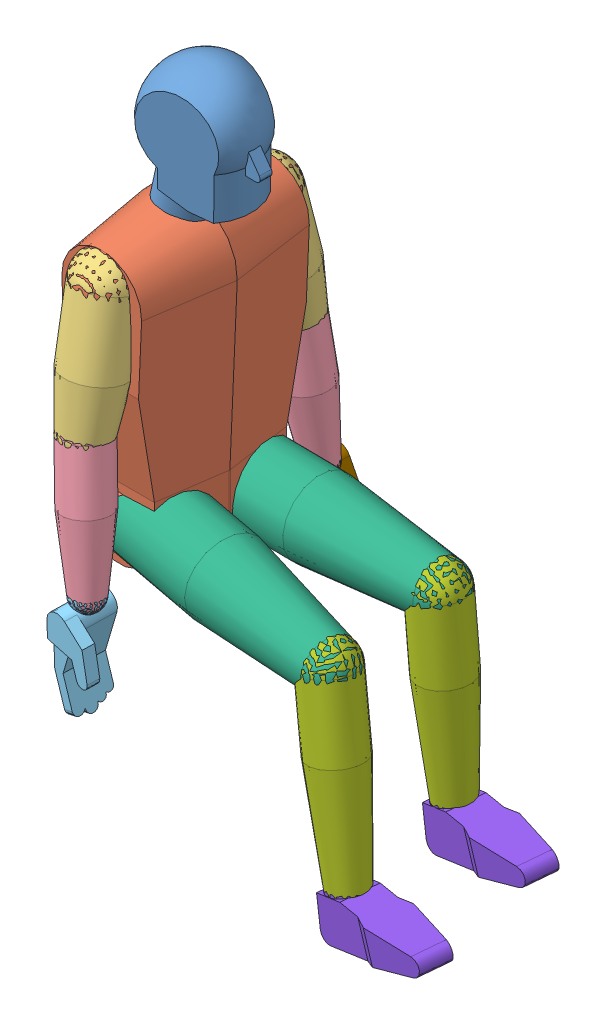
SolidWorks assembly SW3dPS-operator, configuration Default. Lengths in mm.
Overall size (865.46 1323.56 646.61).
14 component instances, 9 part files, 23 mates.
Components (placement in the parent):
- SW3dPS-operator_head-1: SW3dPS-operator_head [Default] at (43.7328 241.1062 1.2045) x (0.015546 0.999874 0.003131) z (-0.014867 -0.0029 0.999885) size (356.87 241.3 163.45)
- SW3dPS-operator_body-1: SW3dPS-operator_body [Default] x (0 0 1) z (-1 0 0) size (464.82 648.24 222.18)
- SW3dPS-operator_upper arm-1: SW3dPS-operator_upper arm [Default] at (0 0 -171.45) x (0.286165 -0.192886 0.938565) z (-0.95694 -0.107363 0.269703) size (121.92 365.76 121.92)
- SW3dPS-operator_upper arm-2: SW3dPS-operator_upper arm [Default] at (0 0 171.45) x (0.082111 0.214474 0.973272) z (-0.99583 -0.021306 0.08871) size (121.92 365.76 121.92)
- SW3dPS-operator_lower arm-1: SW3dPS-operator_lower arm [Default] at (10.2006 -250.5106 225.7928) x (0.548586 0.143645 0.823662) z (-0.828384 -0.040099 0.558724) size (96.52 355.6 96.52)
- SW3dPS-operator_lower arm-2: SW3dPS-operator_lower arm [Default] at (12.5051 -250.2111 -226.6841) x (-0.991468 -0.111533 0.067464) z (-0.075929 0.073473 -0.994403) size (96.52 355.6 96.52)
- SW3dPS-operator_RIGHT HAND-1: SW3dPS-operator_RIGHT HAND [Default] at (34.5967 -560.4207 250.0493) x (-0.179119 -0.981682 -0.064943) z (0.076088 0.05199 -0.995745) size (255.07 109.09 97.79)
- SW3dPS-operator_upper leg-1: SW3dPS-operator_upper leg [Default] at (0 -467.36 -87.63) x (0.008051 0.096282 -0.995322) z (0.004121 0.995342 0.096317) size (160.02 594.36 160.02)
- SW3dPS-operator_upper leg-2: SW3dPS-operator_upper leg [Default] at (0 -467.36 87.63) x (-0.116584 0.140538 0.983187) z (-0.090158 -0.987348 0.130442) size (160.02 594.36 160.02)
- SW3dPS-operator_lower leg-1: SW3dPS-operator_lower leg [Default] at (459.7212 -469.6021 -84.1281) x (-0.934597 -0.079119 -0.346796) z (0.345231 0.03311 -0.937933) size (109.22 469.9 109.22)
- SW3dPS-operator_lower leg-2: SW3dPS-operator_lower leg [Default] at (454.7198 -501.1207 146.3752) x (0.526052 0.038392 -0.849586) z (0.832742 0.179561 0.523736) size (109.22 469.9 109.22)
- SW3dPS-operator_foot-1: SW3dPS-operator_foot [Default] at (516.9741 -930.7291 -86.4832) x (0.947874 0.275098 0.1608) z (-0.151286 -0.055607 0.986925) size (259.65 127 95)
- SW3dPS-operator_foot-2: SW3dPS-operator_foot [Default] at (544.7765 -957.2244 168.959) x (0.947874 0.275098 0.1608) z (-0.151286 -0.055607 0.986925) size (259.65 127 95)
- SW3dPS-operator_LEFT HAND-1: SW3dPS-operator_LEFT HAND [Default] at (-6.4544 -573.4476 102.4429) x (-0.552435 -0.829159 -0.085506) z (0.076088 0.05199 -0.995745) size (255.07 109.09 97.79)
Mates (geometry in assembly coordinates):
- Концентрический1: concentric: sphere of SW3dPS-operator_body-1; sphere of SW3dPS-operator_upper arm-1
- Концентрический2: concentric: sphere of SW3dPS-operator_upper arm-1; sphere of SW3dPS-operator_lower arm-2
- Концентрический3: concentric: sphere of SW3dPS-operator_lower arm-2; sphere of SW3dPS-operator_LEFT HAND-1
- Концентрический4: concentric: sphere of SW3dPS-operator_body-1; sphere of SW3dPS-operator_upper arm-2
- Концентрический5: concentric: sphere of SW3dPS-operator_upper arm-2; sphere of SW3dPS-operator_lower arm-1
- Концентрический6: concentric: sphere of SW3dPS-operator_lower arm-1; sphere of SW3dPS-operator_RIGHT HAND-1
- Концентрический7: concentric: sphere of SW3dPS-operator_lower leg-2; sphere of SW3dPS-operator_foot-2
- Концентрический8: concentric: sphere of SW3dPS-operator_lower leg-1; sphere of SW3dPS-operator_foot-1
- Концентрический9: concentric: sphere of SW3dPS-operator_upper leg-2; sphere of SW3dPS-operator_lower leg-2
- Концентрический10: concentric: sphere of SW3dPS-operator_body-1; sphere of SW3dPS-operator_upper leg-2
- Концентрический11: concentric: sphere of SW3dPS-operator_body-1; sphere of SW3dPS-operator_upper leg-1
- Концентрический12: concentric: sphere of SW3dPS-operator_upper leg-1; sphere of SW3dPS-operator_lower leg-1
- Совпадение1: coincident: point of SW3dPS-operator_body-1; point of assembly
- Концентрический13: concentric: sphere of SW3dPS-operator_body-1; sphere of SW3dPS-operator_head-1
- Совпадение4: coincident: plane of SW3dPS-operator_body-1 through (0 0 0) normal (-1 0 0); plane of assembly through (0 0 0) normal (1 0 0)
- Совпадение5: coincident: plane of SW3dPS-operator_body-1 through (0 0 0) normal (0 1 0); plane of assembly through (0 0 0) normal (0 1 0)
- Параллельность3: parallel: plane of SW3dPS-operator_foot-1 through (547.423 -790.1055 -35.2876) normal (-0.151286 -0.055607 0.986925); plane of SW3dPS-operator_foot-2 through (586.7534 -812.3636 144.9509) normal (0.151286 0.055607 -0.986925)
- Параллельность4: parallel: plane of SW3dPS-operator_foot-1 through (483.9726 -940.8627 -43.9857) normal (0.280443 -0.959807 -0.01109); plane of SW3dPS-operator_foot-2 through (511.775 -967.358 211.4565) normal (0.280443 -0.959807 -0.01109)
- Параллельность5: parallel: plane of SW3dPS-operator_RIGHT HAND-1 through (81.6982 -641.4549 304.8986) normal (-0.076088 -0.05199 0.995745); plane of SW3dPS-operator_LEFT HAND-1 through (41.1992 -644.0396 -310.9158) normal (0.076088 0.05199 -0.995745)
- Заблокировать2: lock: unknown of SW3dPS-operator_body-1; unknown of SW3dPS-operator_upper leg-2
- Заблокировать3: lock: unknown of SW3dPS-operator_body-1; unknown of SW3dPS-operator_upper leg-1
- Заблокировать4: lock: unknown of SW3dPS-operator_upper leg-1; unknown of SW3dPS-operator_lower leg-1
- Заблокировать5: lock: unknown of SW3dPS-operator_upper leg-2; unknown of SW3dPS-operator_lower leg-2
